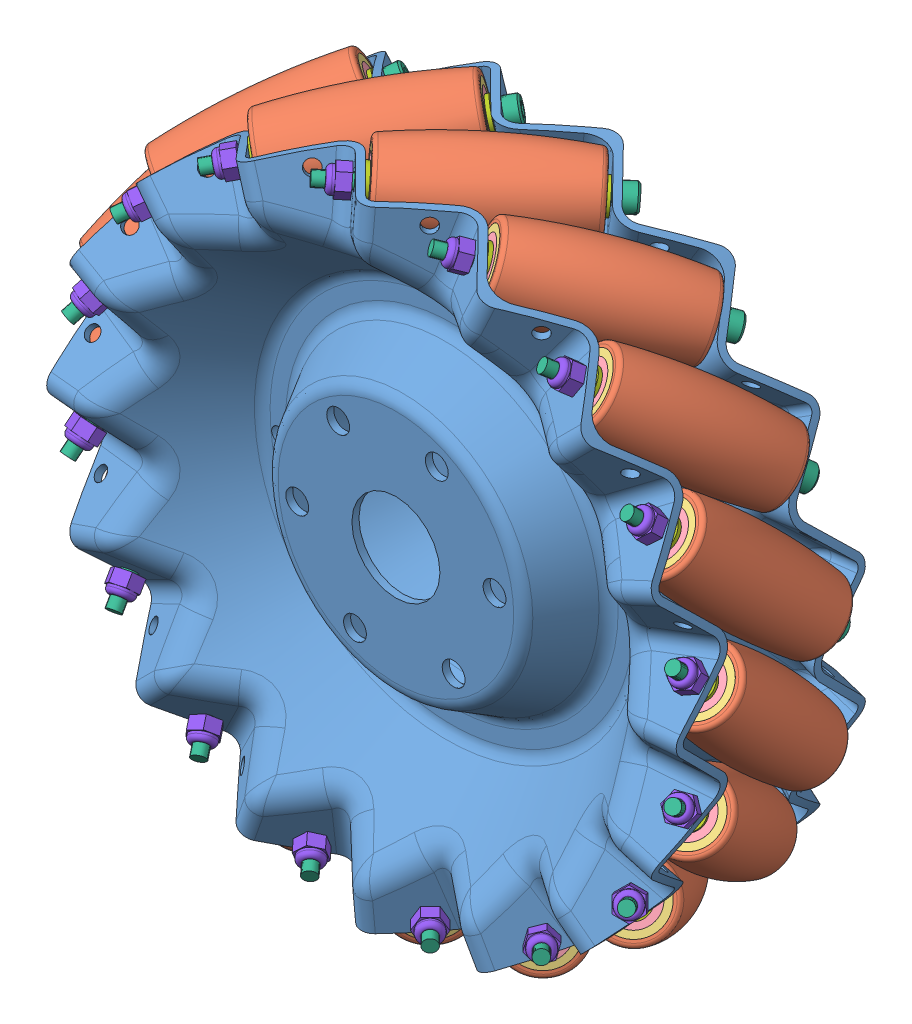
SolidWorks assembly 麦轮, configuration 默认. Lengths in mm.
Overall size (168 168 51.85).
162 component instances, 8 part files, 5 mates.
Components (placement in the parent):
- 麦轮钣金（5）-3: 麦轮钣金（5） [默认] at origin size (142.88 142.88 24.05)
- 麦轮钣金（5）-4: 麦轮钣金（5） [默认] at (0 0 -3.2004) x (0.980785 0.19509 0) z (0 0 -1) size (142.88 142.88 24.05)
- 滚花橡胶轮组装（5）-17: 滚花橡胶轮组装（5） [默认] at (62.8341 -3.4175 25.769) x (-0.837249 0.541411 -0.076735) z (-0.338043 -0.622763 -0.705615) size (18.5 18.5 53)
  - 滚花橡胶轮外（5）-1: 滚花橡胶轮外（5） [默认] at (-9.896 1.7835 38.5971) size (18.5 18.5 38)
  - 滚花铝柱（5）-1: 滚花铝柱（5） [默认] at (-9.896 1.7835 38) x (0.787441 0.61639 0) z (-0.61639 0.787441 0) size (13 38 13)
  - 轴承5X10X4（5）-1: 轴承5X10X4（5） [默认] at (-9.896 1.7835 55) x (0.442498 0.896769 0) z (-0.896769 0.442498 0) size (10 4 10)
  - 轴承5X10X4（5）-2: 轴承5X10X4（5） [默认] at (-9.896 1.7835 21) x (0.442498 0.896769 0) z (-0.896769 0.442498 0) size (10 4 10)
  - 铜管3X5（5）-1: 铜管3X5（5） [默认] at (-9.896 1.7835 38) x (0.823254 0.567673 0) z (-0.567673 0.823254 0) size (5 38 5)
  - 螺丝（5）-1: 螺丝（5） [默认] at (-9.896 1.7835 59.6) x (-0.462621 0.886556 0) z (0 0 1) size (5.5 5.5 53)
  - 垫片（5）-1: 垫片（5） [默认] at (-9.896 1.7835 57) x (1 0 0) z (0 -1 0) size (7 0.8 7)
  - 垫片（5）-2: 垫片（5） [默认] at (-9.896 1.7835 19) x (0.746862 -0.664979 0) z (0.664979 0.746862 0) size (7 0.8 7)
  - 螺母（5）-1: 螺母（5） [默认] at (-9.896 1.7835 16.2) x (-0.766894 0.641774 0) z (0 0 -1) size (6.35 5.5 4.25)
- 滚花橡胶轮组装（5）-18: 滚花橡胶轮组装（5） [默认] at (59.3589 20.8882 25.769) x (-0.980706 0.179798 -0.076735) z (-0.073989 -0.704722 -0.705615) size (18.5 18.5 53)
  - 滚花橡胶轮外（5）-1: 滚花橡胶轮外（5） [默认] at (-9.896 1.7835 38.5971) size (18.5 18.5 38)
  - 滚花铝柱（5）-1: 滚花铝柱（5） [默认] at (-9.896 1.7835 38) x (0.787441 0.61639 0) z (-0.61639 0.787441 0) size (13 38 13)
  - 轴承5X10X4（5）-1: 轴承5X10X4（5） [默认] at (-9.896 1.7835 55) x (0.442498 0.896769 0) z (-0.896769 0.442498 0) size (10 4 10)
  - 轴承5X10X4（5）-2: 轴承5X10X4（5） [默认] at (-9.896 1.7835 21) x (0.442498 0.896769 0) z (-0.896769 0.442498 0) size (10 4 10)
  - 铜管3X5（5）-1: 铜管3X5（5） [默认] at (-9.896 1.7835 38) x (0.823254 0.567673 0) z (-0.567673 0.823254 0) size (5 38 5)
  - 螺丝（5）-1: 螺丝（5） [默认] at (-9.896 1.7835 59.6) x (-0.462621 0.886556 0) z (0 0 1) size (5.5 5.5 53)
  - 垫片（5）-1: 垫片（5） [默认] at (-9.896 1.7835 57) x (1 0 0) z (0 -1 0) size (7 0.8 7)
  - 垫片（5）-2: 垫片（5） [默认] at (-9.896 1.7835 19) x (0.746862 -0.664979 0) z (0.664979 0.746862 0) size (7 0.8 7)
  - 螺母（5）-1: 螺母（5） [默认] at (-9.896 1.7835 16.2) x (-0.766894 0.641774 0) z (0 0 -1) size (6.35 5.5 4.25)
- 滚花橡胶轮组装（5）-19: 滚花橡胶轮组装（5） [默认] at (46.8469 42.0139 25.769) x (-0.97486 -0.209189 -0.076735) z (0.201328 -0.679392 -0.705615) size (18.5 18.5 53)
  - 滚花橡胶轮外（5）-1: 滚花橡胶轮外（5） [默认] at (-9.896 1.7835 38.5971) size (18.5 18.5 38)
  - 滚花铝柱（5）-1: 滚花铝柱（5） [默认] at (-9.896 1.7835 38) x (0.787441 0.61639 0) z (-0.61639 0.787441 0) size (13 38 13)
  - 轴承5X10X4（5）-1: 轴承5X10X4（5） [默认] at (-9.896 1.7835 55) x (0.442498 0.896769 0) z (-0.896769 0.442498 0) size (10 4 10)
  - 轴承5X10X4（5）-2: 轴承5X10X4（5） [默认] at (-9.896 1.7835 21) x (0.442498 0.896769 0) z (-0.896769 0.442498 0) size (10 4 10)
  - 铜管3X5（5）-1: 铜管3X5（5） [默认] at (-9.896 1.7835 38) x (0.823254 0.567673 0) z (-0.567673 0.823254 0) size (5 38 5)
  - 螺丝（5）-1: 螺丝（5） [默认] at (-9.896 1.7835 59.6) x (-0.462621 0.886556 0) z (0 0 1) size (5.5 5.5 53)
  - 垫片（5）-1: 垫片（5） [默认] at (-9.896 1.7835 57) x (1 0 0) z (0 -1 0) size (7 0.8 7)
  - 垫片（5）-2: 垫片（5） [默认] at (-9.896 1.7835 19) x (0.746862 -0.664979 0) z (0.664979 0.746862 0) size (7 0.8 7)
  - 螺母（5）-1: 螺母（5） [默认] at (-9.896 1.7835 16.2) x (-0.766894 0.641774 0) z (0 0 -1) size (6.35 5.5 4.25)
- 滚花橡胶轮组装（5）-20: 滚花橡胶轮组装（5） [默认] at (27.2029 56.7433 25.769) x (-0.8206 -0.566328 -0.076735) z (0.445995 -0.550632 -0.705615) size (18.5 18.5 53)
  - 滚花橡胶轮外（5）-1: 滚花橡胶轮外（5） [默认] at (-9.896 1.7835 38.5971) size (18.5 18.5 38)
  - 滚花铝柱（5）-1: 滚花铝柱（5） [默认] at (-9.896 1.7835 38) x (0.787441 0.61639 0) z (-0.61639 0.787441 0) size (13 38 13)
  - 轴承5X10X4（5）-1: 轴承5X10X4（5） [默认] at (-9.896 1.7835 55) x (0.442498 0.896769 0) z (-0.896769 0.442498 0) size (10 4 10)
  - 轴承5X10X4（5）-2: 轴承5X10X4（5） [默认] at (-9.896 1.7835 21) x (0.442498 0.896769 0) z (-0.896769 0.442498 0) size (10 4 10)
  - 铜管3X5（5）-1: 铜管3X5（5） [默认] at (-9.896 1.7835 38) x (0.823254 0.567673 0) z (-0.567673 0.823254 0) size (5 38 5)
  - 螺丝（5）-1: 螺丝（5） [默认] at (-9.896 1.7835 59.6) x (-0.462621 0.886556 0) z (0 0 1) size (5.5 5.5 53)
  - 垫片（5）-1: 垫片（5） [默认] at (-9.896 1.7835 57) x (1 0 0) z (0 -1 0) size (7 0.8 7)
  - 垫片（5）-2: 垫片（5） [默认] at (-9.896 1.7835 19) x (0.746862 -0.664979 0) z (0.664979 0.746862 0) size (7 0.8 7)
  - 螺母（5）-1: 螺母（5） [默认] at (-9.896 1.7835 16.2) x (-0.766894 0.641774 0) z (0 0 -1) size (6.35 5.5 4.25)
- 滚花橡胶轮组装（5）-21: 滚花橡胶轮组装（5） [默认] at (3.4175 62.8341 25.769) x (-0.541411 -0.837249 -0.076735) z (0.622763 -0.338043 -0.705615) size (18.5 18.5 53)
  - 滚花橡胶轮外（5）-1: 滚花橡胶轮外（5） [默认] at (-9.896 1.7835 38.5971) size (18.5 18.5 38)
  - 滚花铝柱（5）-1: 滚花铝柱（5） [默认] at (-9.896 1.7835 38) x (0.787441 0.61639 0) z (-0.61639 0.787441 0) size (13 38 13)
  - 轴承5X10X4（5）-1: 轴承5X10X4（5） [默认] at (-9.896 1.7835 55) x (0.442498 0.896769 0) z (-0.896769 0.442498 0) size (10 4 10)
  - 轴承5X10X4（5）-2: 轴承5X10X4（5） [默认] at (-9.896 1.7835 21) x (0.442498 0.896769 0) z (-0.896769 0.442498 0) size (10 4 10)
  - 铜管3X5（5）-1: 铜管3X5（5） [默认] at (-9.896 1.7835 38) x (0.823254 0.567673 0) z (-0.567673 0.823254 0) size (5 38 5)
  - 螺丝（5）-1: 螺丝（5） [默认] at (-9.896 1.7835 59.6) x (-0.462621 0.886556 0) z (0 0 1) size (5.5 5.5 53)
  - 垫片（5）-1: 垫片（5） [默认] at (-9.896 1.7835 57) x (1 0 0) z (0 -1 0) size (7 0.8 7)
  - 垫片（5）-2: 垫片（5） [默认] at (-9.896 1.7835 19) x (0.746862 -0.664979 0) z (0.664979 0.746862 0) size (7 0.8 7)
  - 螺母（5）-1: 螺母（5） [默认] at (-9.896 1.7835 16.2) x (-0.766894 0.641774 0) z (0 0 -1) size (6.35 5.5 4.25)
- 滚花橡胶轮组装（5）-22: 滚花橡胶轮组装（5） [默认] at (-20.8882 59.3589 25.769) x (-0.179798 -0.980706 -0.076735) z (0.704722 -0.073989 -0.705615) size (18.5 18.5 53)
  - 滚花橡胶轮外（5）-1: 滚花橡胶轮外（5） [默认] at (-9.896 1.7835 38.5971) size (18.5 18.5 38)
  - 滚花铝柱（5）-1: 滚花铝柱（5） [默认] at (-9.896 1.7835 38) x (0.787441 0.61639 0) z (-0.61639 0.787441 0) size (13 38 13)
  - 轴承5X10X4（5）-1: 轴承5X10X4（5） [默认] at (-9.896 1.7835 55) x (0.442498 0.896769 0) z (-0.896769 0.442498 0) size (10 4 10)
  - 轴承5X10X4（5）-2: 轴承5X10X4（5） [默认] at (-9.896 1.7835 21) x (0.442498 0.896769 0) z (-0.896769 0.442498 0) size (10 4 10)
  - 铜管3X5（5）-1: 铜管3X5（5） [默认] at (-9.896 1.7835 38) x (0.823254 0.567673 0) z (-0.567673 0.823254 0) size (5 38 5)
  - 螺丝（5）-1: 螺丝（5） [默认] at (-9.896 1.7835 59.6) x (-0.462621 0.886556 0) z (0 0 1) size (5.5 5.5 53)
  - 垫片（5）-1: 垫片（5） [默认] at (-9.896 1.7835 57) x (1 0 0) z (0 -1 0) size (7 0.8 7)
  - 垫片（5）-2: 垫片（5） [默认] at (-9.896 1.7835 19) x (0.746862 -0.664979 0) z (0.664979 0.746862 0) size (7 0.8 7)
  - 螺母（5）-1: 螺母（5） [默认] at (-9.896 1.7835 16.2) x (-0.766894 0.641774 0) z (0 0 -1) size (6.35 5.5 4.25)
- 滚花橡胶轮组装（5）-23: 滚花橡胶轮组装（5） [默认] at (-42.0139 46.8469 25.769) x (0.209189 -0.97486 -0.076735) z (0.679392 0.201328 -0.705615) size (18.5 18.5 53)
  - 滚花橡胶轮外（5）-1: 滚花橡胶轮外（5） [默认] at (-9.896 1.7835 38.5971) size (18.5 18.5 38)
  - 滚花铝柱（5）-1: 滚花铝柱（5） [默认] at (-9.896 1.7835 38) x (0.787441 0.61639 0) z (-0.61639 0.787441 0) size (13 38 13)
  - 轴承5X10X4（5）-1: 轴承5X10X4（5） [默认] at (-9.896 1.7835 55) x (0.442498 0.896769 0) z (-0.896769 0.442498 0) size (10 4 10)
  - 轴承5X10X4（5）-2: 轴承5X10X4（5） [默认] at (-9.896 1.7835 21) x (0.442498 0.896769 0) z (-0.896769 0.442498 0) size (10 4 10)
  - 铜管3X5（5）-1: 铜管3X5（5） [默认] at (-9.896 1.7835 38) x (0.823254 0.567673 0) z (-0.567673 0.823254 0) size (5 38 5)
  - 螺丝（5）-1: 螺丝（5） [默认] at (-9.896 1.7835 59.6) x (-0.462621 0.886556 0) z (0 0 1) size (5.5 5.5 53)
  - 垫片（5）-1: 垫片（5） [默认] at (-9.896 1.7835 57) x (1 0 0) z (0 -1 0) size (7 0.8 7)
  - 垫片（5）-2: 垫片（5） [默认] at (-9.896 1.7835 19) x (0.746862 -0.664979 0) z (0.664979 0.746862 0) size (7 0.8 7)
  - 螺母（5）-1: 螺母（5） [默认] at (-9.896 1.7835 16.2) x (-0.766894 0.641774 0) z (0 0 -1) size (6.35 5.5 4.25)
- 滚花橡胶轮组装（5）-24: 滚花橡胶轮组装（5） [默认] at (-56.7433 27.2029 25.769) x (0.566328 -0.8206 -0.076735) z (0.550632 0.445995 -0.705615) size (18.5 18.5 53)
  - 滚花橡胶轮外（5）-1: 滚花橡胶轮外（5） [默认] at (-9.896 1.7835 38.5971) size (18.5 18.5 38)
  - 滚花铝柱（5）-1: 滚花铝柱（5） [默认] at (-9.896 1.7835 38) x (0.787441 0.61639 0) z (-0.61639 0.787441 0) size (13 38 13)
  - 轴承5X10X4（5）-1: 轴承5X10X4（5） [默认] at (-9.896 1.7835 55) x (0.442498 0.896769 0) z (-0.896769 0.442498 0) size (10 4 10)
  - 轴承5X10X4（5）-2: 轴承5X10X4（5） [默认] at (-9.896 1.7835 21) x (0.442498 0.896769 0) z (-0.896769 0.442498 0) size (10 4 10)
  - 铜管3X5（5）-1: 铜管3X5（5） [默认] at (-9.896 1.7835 38) x (0.823254 0.567673 0) z (-0.567673 0.823254 0) size (5 38 5)
  - 螺丝（5）-1: 螺丝（5） [默认] at (-9.896 1.7835 59.6) x (-0.462621 0.886556 0) z (0 0 1) size (5.5 5.5 53)
  - 垫片（5）-1: 垫片（5） [默认] at (-9.896 1.7835 57) x (1 0 0) z (0 -1 0) size (7 0.8 7)
  - 垫片（5）-2: 垫片（5） [默认] at (-9.896 1.7835 19) x (0.746862 -0.664979 0) z (0.664979 0.746862 0) size (7 0.8 7)
  - 螺母（5）-1: 螺母（5） [默认] at (-9.896 1.7835 16.2) x (-0.766894 0.641774 0) z (0 0 -1) size (6.35 5.5 4.25)
- 滚花橡胶轮组装（5）-25: 滚花橡胶轮组装（5） [默认] at (-62.8341 3.4175 25.769) x (0.837249 -0.541411 -0.076735) z (0.338043 0.622763 -0.705615) size (18.5 18.5 53)
  - 滚花橡胶轮外（5）-1: 滚花橡胶轮外（5） [默认] at (-9.896 1.7835 38.5971) size (18.5 18.5 38)
  - 滚花铝柱（5）-1: 滚花铝柱（5） [默认] at (-9.896 1.7835 38) x (0.787441 0.61639 0) z (-0.61639 0.787441 0) size (13 38 13)
  - 轴承5X10X4（5）-1: 轴承5X10X4（5） [默认] at (-9.896 1.7835 55) x (0.442498 0.896769 0) z (-0.896769 0.442498 0) size (10 4 10)
  - 轴承5X10X4（5）-2: 轴承5X10X4（5） [默认] at (-9.896 1.7835 21) x (0.442498 0.896769 0) z (-0.896769 0.442498 0) size (10 4 10)
  - 铜管3X5（5）-1: 铜管3X5（5） [默认] at (-9.896 1.7835 38) x (0.823254 0.567673 0) z (-0.567673 0.823254 0) size (5 38 5)
  - 螺丝（5）-1: 螺丝（5） [默认] at (-9.896 1.7835 59.6) x (-0.462621 0.886556 0) z (0 0 1) size (5.5 5.5 53)
  - 垫片（5）-1: 垫片（5） [默认] at (-9.896 1.7835 57) x (1 0 0) z (0 -1 0) size (7 0.8 7)
  - 垫片（5）-2: 垫片（5） [默认] at (-9.896 1.7835 19) x (0.746862 -0.664979 0) z (0.664979 0.746862 0) size (7 0.8 7)
  - 螺母（5）-1: 螺母（5） [默认] at (-9.896 1.7835 16.2) x (-0.766894 0.641774 0) z (0 0 -1) size (6.35 5.5 4.25)
- 滚花橡胶轮组装（5）-26: 滚花橡胶轮组装（5） [默认] at (-59.3589 -20.8882 25.769) x (0.980706 -0.179798 -0.076735) z (0.073989 0.704722 -0.705615) size (18.5 18.5 53)
  - 滚花橡胶轮外（5）-1: 滚花橡胶轮外（5） [默认] at (-9.896 1.7835 38.5971) size (18.5 18.5 38)
  - 滚花铝柱（5）-1: 滚花铝柱（5） [默认] at (-9.896 1.7835 38) x (0.787441 0.61639 0) z (-0.61639 0.787441 0) size (13 38 13)
  - 轴承5X10X4（5）-1: 轴承5X10X4（5） [默认] at (-9.896 1.7835 55) x (0.442498 0.896769 0) z (-0.896769 0.442498 0) size (10 4 10)
  - 轴承5X10X4（5）-2: 轴承5X10X4（5） [默认] at (-9.896 1.7835 21) x (0.442498 0.896769 0) z (-0.896769 0.442498 0) size (10 4 10)
  - 铜管3X5（5）-1: 铜管3X5（5） [默认] at (-9.896 1.7835 38) x (0.823254 0.567673 0) z (-0.567673 0.823254 0) size (5 38 5)
  - 螺丝（5）-1: 螺丝（5） [默认] at (-9.896 1.7835 59.6) x (-0.462621 0.886556 0) z (0 0 1) size (5.5 5.5 53)
  - 垫片（5）-1: 垫片（5） [默认] at (-9.896 1.7835 57) x (1 0 0) z (0 -1 0) size (7 0.8 7)
  - 垫片（5）-2: 垫片（5） [默认] at (-9.896 1.7835 19) x (0.746862 -0.664979 0) z (0.664979 0.746862 0) size (7 0.8 7)
  - 螺母（5）-1: 螺母（5） [默认] at (-9.896 1.7835 16.2) x (-0.766894 0.641774 0) z (0 0 -1) size (6.35 5.5 4.25)
- 滚花橡胶轮组装（5）-27: 滚花橡胶轮组装（5） [默认] at (-46.8469 -42.0139 25.769) x (0.97486 0.209189 -0.076735) z (-0.201328 0.679392 -0.705615) size (18.5 18.5 53)
  - 滚花橡胶轮外（5）-1: 滚花橡胶轮外（5） [默认] at (-9.896 1.7835 38.5971) size (18.5 18.5 38)
  - 滚花铝柱（5）-1: 滚花铝柱（5） [默认] at (-9.896 1.7835 38) x (0.787441 0.61639 0) z (-0.61639 0.787441 0) size (13 38 13)
  - 轴承5X10X4（5）-1: 轴承5X10X4（5） [默认] at (-9.896 1.7835 55) x (0.442498 0.896769 0) z (-0.896769 0.442498 0) size (10 4 10)
  - 轴承5X10X4（5）-2: 轴承5X10X4（5） [默认] at (-9.896 1.7835 21) x (0.442498 0.896769 0) z (-0.896769 0.442498 0) size (10 4 10)
  - 铜管3X5（5）-1: 铜管3X5（5） [默认] at (-9.896 1.7835 38) x (0.823254 0.567673 0) z (-0.567673 0.823254 0) size (5 38 5)
  - 螺丝（5）-1: 螺丝（5） [默认] at (-9.896 1.7835 59.6) x (-0.462621 0.886556 0) z (0 0 1) size (5.5 5.5 53)
  - 垫片（5）-1: 垫片（5） [默认] at (-9.896 1.7835 57) x (1 0 0) z (0 -1 0) size (7 0.8 7)
  - 垫片（5）-2: 垫片（5） [默认] at (-9.896 1.7835 19) x (0.746862 -0.664979 0) z (0.664979 0.746862 0) size (7 0.8 7)
  - 螺母（5）-1: 螺母（5） [默认] at (-9.896 1.7835 16.2) x (-0.766894 0.641774 0) z (0 0 -1) size (6.35 5.5 4.25)
- 滚花橡胶轮组装（5）-28: 滚花橡胶轮组装（5） [默认] at (-27.2029 -56.7433 25.769) x (0.8206 0.566328 -0.076735) z (-0.445995 0.550632 -0.705615) size (18.5 18.5 53)
  - 滚花橡胶轮外（5）-1: 滚花橡胶轮外（5） [默认] at (-9.896 1.7835 38.5971) size (18.5 18.5 38)
  - 滚花铝柱（5）-1: 滚花铝柱（5） [默认] at (-9.896 1.7835 38) x (0.787441 0.61639 0) z (-0.61639 0.787441 0) size (13 38 13)
  - 轴承5X10X4（5）-1: 轴承5X10X4（5） [默认] at (-9.896 1.7835 55) x (0.442498 0.896769 0) z (-0.896769 0.442498 0) size (10 4 10)
  - 轴承5X10X4（5）-2: 轴承5X10X4（5） [默认] at (-9.896 1.7835 21) x (0.442498 0.896769 0) z (-0.896769 0.442498 0) size (10 4 10)
  - 铜管3X5（5）-1: 铜管3X5（5） [默认] at (-9.896 1.7835 38) x (0.823254 0.567673 0) z (-0.567673 0.823254 0) size (5 38 5)
  - 螺丝（5）-1: 螺丝（5） [默认] at (-9.896 1.7835 59.6) x (-0.462621 0.886556 0) z (0 0 1) size (5.5 5.5 53)
  - 垫片（5）-1: 垫片（5） [默认] at (-9.896 1.7835 57) x (1 0 0) z (0 -1 0) size (7 0.8 7)
  - 垫片（5）-2: 垫片（5） [默认] at (-9.896 1.7835 19) x (0.746862 -0.664979 0) z (0.664979 0.746862 0) size (7 0.8 7)
  - 螺母（5）-1: 螺母（5） [默认] at (-9.896 1.7835 16.2) x (-0.766894 0.641774 0) z (0 0 -1) size (6.35 5.5 4.25)
- 滚花橡胶轮组装（5）-29: 滚花橡胶轮组装（5） [默认] at (-3.4175 -62.8341 25.769) x (0.541411 0.837249 -0.076735) z (-0.622763 0.338043 -0.705615) size (18.5 18.5 53)
  - 滚花橡胶轮外（5）-1: 滚花橡胶轮外（5） [默认] at (-9.896 1.7835 38.5971) size (18.5 18.5 38)
  - 滚花铝柱（5）-1: 滚花铝柱（5） [默认] at (-9.896 1.7835 38) x (0.787441 0.61639 0) z (-0.61639 0.787441 0) size (13 38 13)
  - 轴承5X10X4（5）-1: 轴承5X10X4（5） [默认] at (-9.896 1.7835 55) x (0.442498 0.896769 0) z (-0.896769 0.442498 0) size (10 4 10)
  - 轴承5X10X4（5）-2: 轴承5X10X4（5） [默认] at (-9.896 1.7835 21) x (0.442498 0.896769 0) z (-0.896769 0.442498 0) size (10 4 10)
  - 铜管3X5（5）-1: 铜管3X5（5） [默认] at (-9.896 1.7835 38) x (0.823254 0.567673 0) z (-0.567673 0.823254 0) size (5 38 5)
  - 螺丝（5）-1: 螺丝（5） [默认] at (-9.896 1.7835 59.6) x (-0.462621 0.886556 0) z (0 0 1) size (5.5 5.5 53)
  - 垫片（5）-1: 垫片（5） [默认] at (-9.896 1.7835 57) x (1 0 0) z (0 -1 0) size (7 0.8 7)
  - 垫片（5）-2: 垫片（5） [默认] at (-9.896 1.7835 19) x (0.746862 -0.664979 0) z (0.664979 0.746862 0) size (7 0.8 7)
  - 螺母（5）-1: 螺母（5） [默认] at (-9.896 1.7835 16.2) x (-0.766894 0.641774 0) z (0 0 -1) size (6.35 5.5 4.25)
- 滚花橡胶轮组装（5）-30: 滚花橡胶轮组装（5） [默认] at (20.8882 -59.3589 25.769) x (0.179798 0.980706 -0.076735) z (-0.704722 0.073989 -0.705615) size (18.5 18.5 53)
  - 滚花橡胶轮外（5）-1: 滚花橡胶轮外（5） [默认] at (-9.896 1.7835 38.5971) size (18.5 18.5 38)
  - 滚花铝柱（5）-1: 滚花铝柱（5） [默认] at (-9.896 1.7835 38) x (0.787441 0.61639 0) z (-0.61639 0.787441 0) size (13 38 13)
  - 轴承5X10X4（5）-1: 轴承5X10X4（5） [默认] at (-9.896 1.7835 55) x (0.442498 0.896769 0) z (-0.896769 0.442498 0) size (10 4 10)
  - 轴承5X10X4（5）-2: 轴承5X10X4（5） [默认] at (-9.896 1.7835 21) x (0.442498 0.896769 0) z (-0.896769 0.442498 0) size (10 4 10)
  - 铜管3X5（5）-1: 铜管3X5（5） [默认] at (-9.896 1.7835 38) x (0.823254 0.567673 0) z (-0.567673 0.823254 0) size (5 38 5)
  - 螺丝（5）-1: 螺丝（5） [默认] at (-9.896 1.7835 59.6) x (-0.462621 0.886556 0) z (0 0 1) size (5.5 5.5 53)
  - 垫片（5）-1: 垫片（5） [默认] at (-9.896 1.7835 57) x (1 0 0) z (0 -1 0) size (7 0.8 7)
  - 垫片（5）-2: 垫片（5） [默认] at (-9.896 1.7835 19) x (0.746862 -0.664979 0) z (0.664979 0.746862 0) size (7 0.8 7)
  - 螺母（5）-1: 螺母（5） [默认] at (-9.896 1.7835 16.2) x (-0.766894 0.641774 0) z (0 0 -1) size (6.35 5.5 4.25)
- 滚花橡胶轮组装（5）-31: 滚花橡胶轮组装（5） [默认] at (42.0139 -46.8469 25.769) x (-0.209189 0.97486 -0.076735) z (-0.679392 -0.201328 -0.705615) size (18.5 18.5 53)
  - 滚花橡胶轮外（5）-1: 滚花橡胶轮外（5） [默认] at (-9.896 1.7835 38.5971) size (18.5 18.5 38)
  - 滚花铝柱（5）-1: 滚花铝柱（5） [默认] at (-9.896 1.7835 38) x (0.787441 0.61639 0) z (-0.61639 0.787441 0) size (13 38 13)
  - 轴承5X10X4（5）-1: 轴承5X10X4（5） [默认] at (-9.896 1.7835 55) x (0.442498 0.896769 0) z (-0.896769 0.442498 0) size (10 4 10)
  - 轴承5X10X4（5）-2: 轴承5X10X4（5） [默认] at (-9.896 1.7835 21) x (0.442498 0.896769 0) z (-0.896769 0.442498 0) size (10 4 10)
  - 铜管3X5（5）-1: 铜管3X5（5） [默认] at (-9.896 1.7835 38) x (0.823254 0.567673 0) z (-0.567673 0.823254 0) size (5 38 5)
  - 螺丝（5）-1: 螺丝（5） [默认] at (-9.896 1.7835 59.6) x (-0.462621 0.886556 0) z (0 0 1) size (5.5 5.5 53)
  - 垫片（5）-1: 垫片（5） [默认] at (-9.896 1.7835 57) x (1 0 0) z (0 -1 0) size (7 0.8 7)
  - 垫片（5）-2: 垫片（5） [默认] at (-9.896 1.7835 19) x (0.746862 -0.664979 0) z (0.664979 0.746862 0) size (7 0.8 7)
  - 螺母（5）-1: 螺母（5） [默认] at (-9.896 1.7835 16.2) x (-0.766894 0.641774 0) z (0 0 -1) size (6.35 5.5 4.25)
- 滚花橡胶轮组装（5）-32: 滚花橡胶轮组装（5） [默认] at (56.7433 -27.2029 25.769) x (-0.566328 0.8206 -0.076735) z (-0.550632 -0.445995 -0.705615) size (18.5 18.5 53)
  - 滚花橡胶轮外（5）-1: 滚花橡胶轮外（5） [默认] at (-9.896 1.7835 38.5971) size (18.5 18.5 38)
  - 滚花铝柱（5）-1: 滚花铝柱（5） [默认] at (-9.896 1.7835 38) x (0.787441 0.61639 0) z (-0.61639 0.787441 0) size (13 38 13)
  - 轴承5X10X4（5）-1: 轴承5X10X4（5） [默认] at (-9.896 1.7835 55) x (0.442498 0.896769 0) z (-0.896769 0.442498 0) size (10 4 10)
  - 轴承5X10X4（5）-2: 轴承5X10X4（5） [默认] at (-9.896 1.7835 21) x (0.442498 0.896769 0) z (-0.896769 0.442498 0) size (10 4 10)
  - 铜管3X5（5）-1: 铜管3X5（5） [默认] at (-9.896 1.7835 38) x (0.823254 0.567673 0) z (-0.567673 0.823254 0) size (5 38 5)
  - 螺丝（5）-1: 螺丝（5） [默认] at (-9.896 1.7835 59.6) x (-0.462621 0.886556 0) z (0 0 1) size (5.5 5.5 53)
  - 垫片（5）-1: 垫片（5） [默认] at (-9.896 1.7835 57) x (1 0 0) z (0 -1 0) size (7 0.8 7)
  - 垫片（5）-2: 垫片（5） [默认] at (-9.896 1.7835 19) x (0.746862 -0.664979 0) z (0.664979 0.746862 0) size (7 0.8 7)
  - 螺母（5）-1: 螺母（5） [默认] at (-9.896 1.7835 16.2) x (-0.766894 0.641774 0) z (0 0 -1) size (6.35 5.5 4.25)
Mates (geometry in assembly coordinates):
- 同心3: concentric anti-aligned: cylinder of 麦轮钣金（5）-3 through (22.3917 2.2054 12.7) axis (0 0 1) radius 2.6; cylinder of 麦轮钣金（5）-4 through (22.3917 2.2054 -15.9004) axis (0 0 -1) radius 2.6
- 同心4: concentric anti-aligned: cylinder of 麦轮钣金（5）-3 through (-9.2859 -20.4944 12.7) axis (0 0 1) radius 2.6; cylinder of 麦轮钣金（5）-4 through (-9.2859 -20.4944 -15.9004) axis (0 0 -1) radius 2.6
- 重合2: coincident anti-aligned: plane of 麦轮钣金（5）-3 through (14.5256 73.025 -1.6002) normal (0 0 -1); plane of 麦轮钣金（5）-4 through (28.4929 -68.788 -1.6002) normal (0 0 1)
- 同心5: concentric anti-aligned: cylinder of 麦轮钣金（5）-4 through (52.2796 -43.8881 -15.6535) axis (0.338043 0.622763 0.705615) radius 1.5875; cylinder of 滚花橡胶轮组装（5）-17/螺丝（5）-1 through (68.6408 -13.7465 18.4981) axis (-0.338043 -0.622763 -0.705615) radius 1.5
- 重合3: coincident anti-aligned: plane of 麦轮钣金（5）-4 through (62.6303 -23.0933 -41.2331) normal (-0.338043 -0.622763 -0.705615); plane of 滚花橡胶轮组装（5）-17/螺丝（5）-1 through (53.8517 -44.1963 -18.4024) normal (0.338043 0.622763 0.705615)
